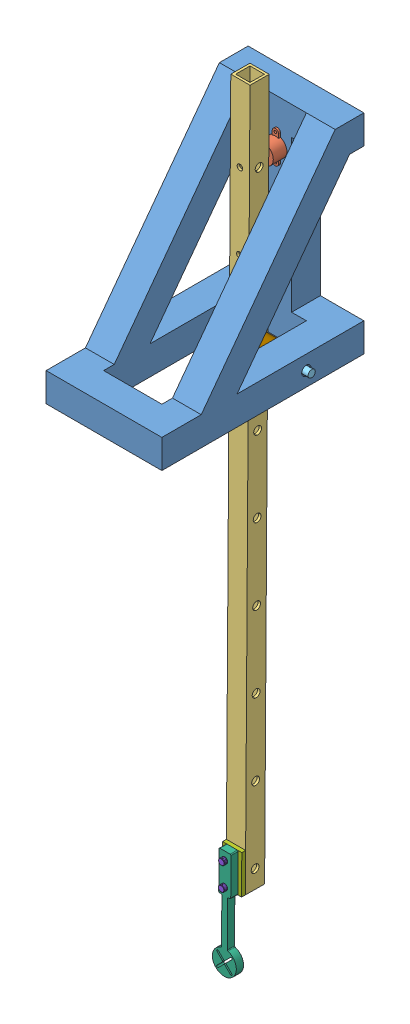
SolidWorks assembly assy_test_stand, configuration Default. Lengths in mm.
Overall size (160 1015.82 267).
18 component instances, 10 part files, 27 mates.
Components (placement in the parent):
- prt_stand-1: prt_stand [Default] at (-6.3403 -49.4173 36.9191) size (153 276 267)
- prt_load_cell-1: prt_load_cell [Default] at (-6.3403 169.2921 -58.5809) x (1 0 0) z (0 -1 0) size (25.5 20.5 42.85)
- prt_arm-1: prt_arm [Default] at (-6.3403 269.5761 -22.5638) x (0 0.00661 0.999978) z (0 -0.999978 0.00661) size (25.4 25.4 923.8)
- prt_sleeve_bearing_0.375x.25-1: prt_sleeve_bearing_0.375x.25 [Default] at (-32.2661 -30.4173 -20.5809) x (0 1 0) z (0 0 1) size (17.46 6.35 17.46)
- prt_sleeve_bearing_0.375x.25-2: prt_sleeve_bearing_0.375x.25 [Default] at (-31.6144 -30.4173 -20.5809) x (0 -0.986279 -0.165085) z (0 -0.165085 0.986279) size (17.46 6.35 17.46)
- prt_sleeve_bearing_0.375x.25-3: prt_sleeve_bearing_0.375x.25 [Default] at (18.9339 -30.4173 -20.5809) x (0 0.381849 -0.924225) z (0 0.924225 0.381849) size (17.46 6.35 17.46)
- prt_sleeve_bearing_0.375x.25-4: prt_sleeve_bearing_0.375x.25 [Default] at (19.5856 -30.4173 -20.5809) x (0 -0.381849 0.924225) z (0 0.924225 0.381849) size (17.46 6.35 17.46)
- prt_shaft-1: prt_shaft [Default] at (-82.8403 -30.4173 -20.5809) x (0 -1 0) z (0 0 1) size (9.53 160 9.53)
- prt_6435K330-1: prt_6435K330 [6435K33] at (-38.4903 -30.4173 -20.5809) x (0 0 1) z (-1 0 0) (suppressed, hidden)
- prt_6435K330-2: prt_6435K330 [6435K33] at (12.7097 -30.4173 -20.5809) x (0 -0.95948 0.281778) z (-1 0 0) (suppressed, hidden)
- prt_6435K330-3: prt_6435K330 [6435K33] at (-25.3903 -30.4173 -20.5809) x (0 0 1) z (-1 0 0) (suppressed, hidden)
- prt_6435K330-4: prt_6435K330 [6435K33] at (25.8097 -30.4173 -20.5809) x (0 -0.95948 0.281778) z (-1 0 0) (suppressed, hidden)
- prt_motor_mount_plate-1: prt_motor_mount_plate [Default] at (-6.3403 -654.0232 10.8466) x (-1 0 0) z (0 -0.999978 0.00661) size (31.75 9.53 142.88)
- prt_neoprene_dampener-1: prt_neoprene_dampener [Default] at (4.0253 -629.6018 1.1599) x (1 0 0) z (0 0.999978 -0.00661) size (25.4 5.08 50.8)
- prt_91746A127-1: prt_91746A127 [91746A127] at (-6.3403 -643.8635 10.7794) x (-0.915546 0.402205 -0.002658) z (0 0.00661 0.999978) size (7.94 7.94 17.76)
- prt_91746A127-2: prt_91746A127 [91746A127] at (-6.3403 -613.3841 10.5779) x (1 0 0) z (0 0.00661 0.999978) size (7.94 7.94 17.76)
- prt_shaft_spacer-1: prt_shaft_spacer [Default] at (-20.6278 -30.4173 -20.5809) x (0 -0.476257 0.879306) z (0 -0.879306 -0.476257) size (25.4 22.61 25.4)
- prt_shaft_spacer-2: prt_shaft_spacer [Default] at (30.5532 -30.4173 -20.5809) x (0 -0.051309 0.998683) z (0 -0.998683 -0.051309) size (25.4 22.61 25.4)
Mates (geometry in assembly coordinates):
- Coincident1: coincident anti-aligned: plane of prt_stand-1 through (-44.8403 -11.4173 -58.5809) normal (0 0 1); plane of prt_load_cell-1 through (-6.3403 169.2921 -58.5809) normal (0 0 -1)
- Coincident2: coincident aligned: plane of prt_stand-1 through (-6.3403 -49.4173 36.9191) normal (1 0 0); plane of prt_load_cell-1
- Concentric1: concentric anti-aligned: cylinder of prt_stand-1 through (-82.8403 -30.4173 -20.5809) axis (1 0 0) radius 6.25; cylinder of prt_arm-1 through (6.3597 -30.4173 -20.5809) axis (-1 0 0) radius 5.175
- Coincident3: coincident anti-aligned: plane of prt_stand-1 through (-6.3403 -49.4173 36.9191) normal (1 0 0); plane of prt_arm-1
- Concentric2: concentric anti-aligned: cylinder of prt_arm-1 through (6.3597 -30.4173 -20.5809) axis (-1 0 0) radius 5.175; cylinder of prt_sleeve_bearing_0.375x.25-1 through (22.7339 -30.4173 -20.5809) axis (1 0 0) radius 6.35
- Coincident4: coincident anti-aligned: plane of prt_arm-1 through (-19.0403 -654.2877 -29.1576) normal (-1 0 0); plane of prt_sleeve_bearing_0.375x.25-1 through (-19.0403 -21.6861 -20.5809) normal (1 0 0)
- Concentric3: concentric aligned: cylinder of prt_arm-1 through (6.3597 -30.4173 -20.5809) axis (-1 0 0) radius 5.175; cylinder of prt_sleeve_bearing_0.375x.25-4 through (-35.4144 -30.4173 -20.5809) axis (-1 0 0) radius 6.35
- Coincident5: coincident anti-aligned: plane of prt_arm-1 through (6.3597 -654.2877 -29.1576) normal (1 0 0); plane of prt_sleeve_bearing_0.375x.25-4 through (6.3597 -33.7514 -12.5113) normal (-1 0 0)
- Concentric4: concentric aligned: cylinder of prt_stand-1 through (-82.8403 -30.4173 -20.5809) axis (1 0 0) radius 6.25; cylinder of prt_sleeve_bearing_0.375x.25-3 through (73.9339 -30.4173 -20.5809) axis (1 0 0) radius 4.7625
- Coincident6: coincident anti-aligned: plane of prt_stand-1 through (32.1597 -11.4173 -58.5809) normal (-1 0 0); plane of prt_sleeve_bearing_0.375x.25-3 through (32.1597 -27.0833 -28.6506) normal (1 0 0)
- Concentric5: concentric anti-aligned: cylinder of prt_stand-1 through (-82.8403 -30.4173 -20.5809) axis (1 0 0) radius 6.25; cylinder of prt_sleeve_bearing_0.375x.25-2 through (-86.6144 -30.4173 -20.5809) axis (-1 0 0) radius 6.35
- Coincident7: coincident anti-aligned: plane of prt_stand-1 through (-44.8403 -11.4173 -58.5809) normal (1 0 0); plane of prt_sleeve_bearing_0.375x.25-2 through (-44.8403 -39.0288 -22.0223) normal (-1 0 0)
- Concentric6: concentric anti-aligned: cylinder of prt_stand-1 through (-82.8403 -30.4173 -20.5809) axis (1 0 0) radius 6.25; cylinder of prt_shaft-1 through (77.1597 -30.4173 -20.5809) axis (-1 0 0) radius 4.7625
- Coincident8: coincident aligned: plane of prt_stand-1 through (-82.8403 -11.4173 -96.5809) normal (-1 0 0); plane of prt_shaft-1 through (-82.8403 -30.4173 -20.5809) normal (-1 0 0)
- Concentric7: concentric anti-aligned: cylinder of prt_shaft-1 through (77.1597 -30.4173 -20.5809) axis (-1 0 0) radius 4.7625; cylinder of prt_6435K330-1 through (-43.2528 -30.4173 -20.5809) axis (1 0 0) radius 4.7625
- Coincident9: coincident anti-aligned: plane of prt_sleeve_bearing_0.375x.25-2 through (-43.2528 -35.1145 -21.3671) normal (1 0 0); plane of prt_6435K330-1 through (-43.2528 -30.4173 -20.5809) normal (-1 0 0)
- Concentric8: concentric anti-aligned: cylinder of prt_shaft-1 through (77.1597 -30.4173 -20.5809) axis (-1 0 0) radius 4.7625; cylinder of prt_6435K330-2 through (7.9472 -30.4173 -20.5809) axis (1 0 0) radius 4.7625
- Coincident11: coincident anti-aligned: plane of prt_sleeve_bearing_0.375x.25-4 through (7.9472 -32.2359 -16.1793) normal (1 0 0); plane of prt_6435K330-2 through (7.9472 -30.4173 -20.5809) normal (-1 0 0)
- Concentric9: concentric anti-aligned: cylinder of prt_shaft-1 through (77.1597 -30.4173 -20.5809) axis (-1 0 0) radius 4.7625; cylinder of prt_6435K330-4 through (21.0472 -30.4173 -20.5809) axis (1 0 0) radius 4.7625
- Coincident12: coincident anti-aligned: plane of prt_sleeve_bearing_0.375x.25-3 through (30.5722 -28.5988 -24.9825) normal (-1 0 0); plane of prt_6435K330-4 through (30.5722 -30.4173 -20.5809) normal (1 0 0)
- Coincident16: coincident anti-aligned: plane of prt_arm-1 through (-19.0403 -654.1198 -3.7581) normal (0 0.00661 0.999978); plane of prt_neoprene_dampener-1 through (-19.0403 -603.3209 -4.0939) normal (0 -0.00661 -0.999978)
- Coincident17: coincident aligned: plane of prt_arm-1 through (6.3597 -654.2877 -29.1576) normal (1 0 0); plane of prt_neoprene_dampener-1 through (6.3597 -654.1198 -3.7581) normal (1 0 0)
- Coincident18: coincident aligned: plane of prt_arm-1 through (6.3597 -654.2877 -29.1576) normal (0 -0.999978 0.00661); plane of prt_neoprene_dampener-1 through (-19.0403 -654.1198 -3.7581) normal (0 -0.999978 0.00661)
- Concentric12: concentric anti-aligned: cylinder of prt_shaft-1 through (77.1597 -30.4173 -20.5809) axis (-1 0 0) radius 4.7625; cylinder of prt_shaft_spacer-1 through (-43.2338 -30.4173 -20.5809) axis (1 0 0) radius 4.826
- Coincident23: coincident anti-aligned: plane of prt_sleeve_bearing_0.375x.25-1 through (-20.6278 -25.6548 -20.5809) normal (-1 0 0); plane of prt_shaft_spacer-1 through (-20.6278 -30.4173 -20.5809) normal (1 0 0)
- Concentric13: concentric anti-aligned: cylinder of prt_shaft-1 through (77.1597 -30.4173 -20.5809) axis (-1 0 0) radius 4.7625; cylinder of prt_shaft_spacer-2 through (7.9472 -30.4173 -20.5809) axis (1 0 0) radius 4.826
- Coincident24: coincident anti-aligned: plane of prt_sleeve_bearing_0.375x.25-4 through (7.9472 -32.2359 -16.1793) normal (1 0 0); plane of prt_shaft_spacer-2 through (7.9472 -30.4173 -20.5809) normal (-1 0 0)
